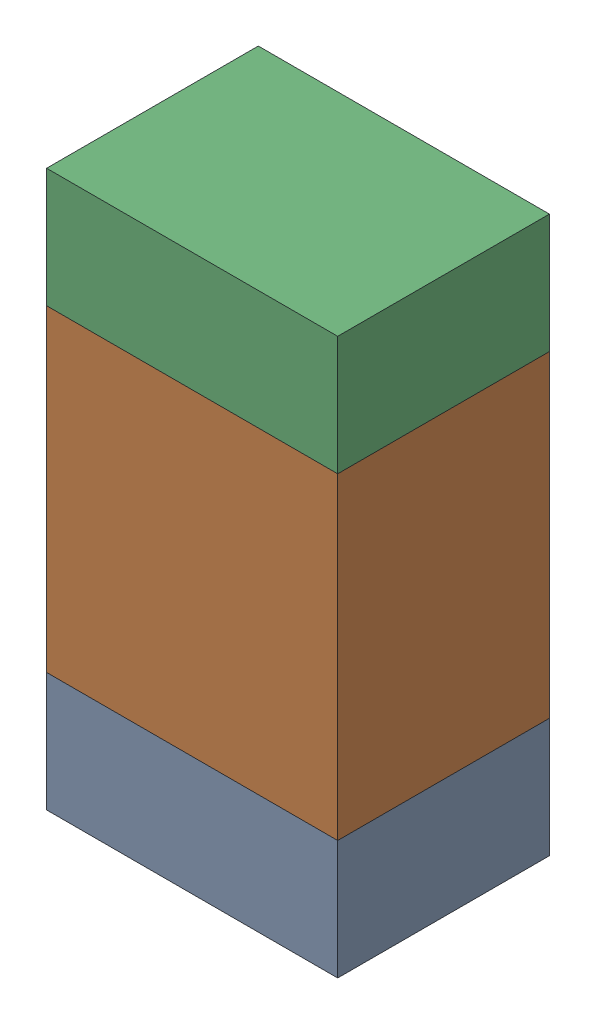
SolidWorks assembly R113_1PCB, configuration Default. Lengths in mm.
Overall size (0.55 1.05 0.4).
6 component instances, 2 part files, 0 mates.
Components (placement in the parent):
- 846483288-1: 846483288 [Default] at (115.6999 109.5876 0) size (0.55 0.22 0.4)
  - Extruded_12-1: Extruded_12 [Default] at origin size (0.55 0.22 0.4)
- 846483424-1: 846483424 [Default] at (115.6999 110.0001 0) size (0.55 0.6 0.4)
  - Extruded_13-1: Extruded_13 [Default] at origin size (0.55 0.6 0.4)
- 846483288-2: 846483288 [Default] at (115.6999 110.4126 0) size (0.55 0.22 0.4)
  - Extruded_12-1: Extruded_12 [Default] at origin size (0.55 0.22 0.4)
